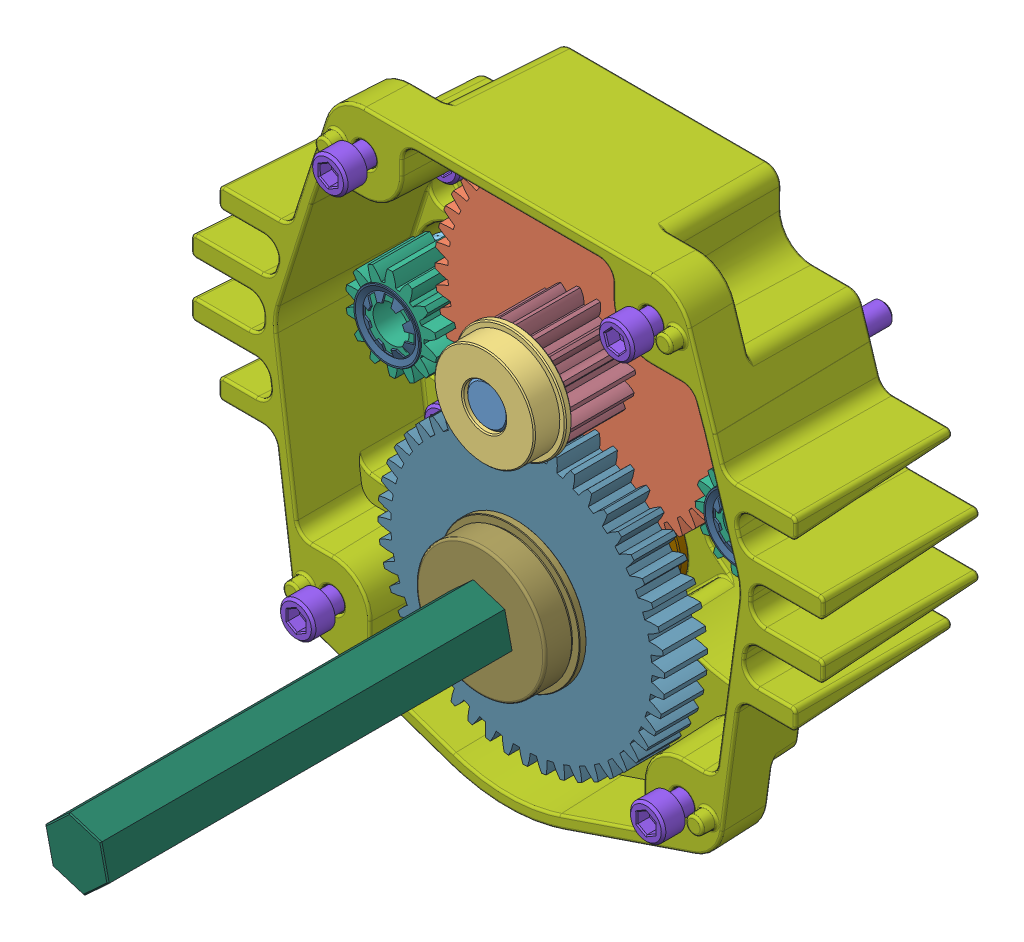
SolidWorks assembly ToughboxMini, configuration Default. Lengths in mm.
Overall size (140.05 127.01 142.29).
31 component instances, 15 part files, 74 mates.
Components (placement in the parent):
- TBMiniSmallHexShaft-1: TBMiniSmallHexShaft [Default] at (-129.7894 33.1737 -52.3959) x (-0.674239 -0.738513 0) z (-0.738513 0.674239 0) size (11 38.23 9.52)
- LargeClusterGear_Hex_50t0.375-1: LargeClusterGear_Hex_50t0.375 [Default] at (-91.0349 50.9043 -67.5597) x (-0.674239 -0.738513 0) z (0 0 -1) size (65.97 66.04 10.16)
- Bearing_FR6ZZ-1: Bearing_FR6ZZ [Default] at (-96.247 60.278 -52.5991) x (-0.893862 0.448342 0) z (0 0 1) size (24.69 24.69 7.16)
- NylockNut_10-32-1: NylockNut_10-32 [Default] at (-129.8464 -8.0737 -56.3837) x (0.501678 0.865055 0) z (0 0 -1) size (10.18 11.01 7.1)
- NylockNut_10-32-2: NylockNut_10-32 [Default] at (-59.2462 80.7349 -56.3837) x (0.999999 -0.001296 0) z (0 0 -1) size (10.18 11.01 7.1)
- NylockNut_10-32-3: NylockNut_10-32 [Default] at (-122.7461 80.8172 -56.3837) x (0.500567 0.865698 0) z (0 0 -1) size (10.18 11.01 7.1)
- NylockNut_10-32-4: NylockNut_10-32 [Default] at (-52.3764 -8.1741 -56.3837) x (-0.501678 -0.865055 0) z (0 0 -1) size (10.18 11.01 7.1)
- Washer_5-16-1: Washer_5-16 [Default] at (-52.3162 38.3079 -77.7705) x (-0.418041 0.908428 0) z (0 0 -1) size (17.53 17.53 1.47)
- Washer_5-16-2: Washer_5-16 [Default] at (-52.3162 38.3079 -76.2973) x (0.897267 -0.441488 0) z (0 0 -1) size (17.53 17.53 1.47)
- Washer_5-16-3: Washer_5-16 [Default] at (-129.7861 38.4083 -77.7705) x (-0.990116 0.140253 0) z (0 0 1) size (17.53 17.53 1.47)
- Washer_5-16-4: Washer_5-16 [Default] at (-129.7861 38.4083 -79.2437) x (-0.681761 0.731575 0) z (0 0 1) size (17.53 17.53 1.47)
- CIMGear_14t8mm-1: CIMGear_14t8mm [Default] at (-52.3162 38.3079 -63.5973) x (-0.082762 0.996569 0) z (0 0 -1) size (20.03 20.32 12.7)
- CIMGear_14t8mm-2: CIMGear_14t8mm [Default] at (-129.7861 38.4083 -63.5973) x (0.603285 0.797525 0) z (0 0 -1) size (20.03 20.32 12.7)
- TBMiniHousing-1: TBMiniHousing [Default] at (-91.0876 10.1882 -86.3557) x (0.999999 -0.001296 0) z (0 0 1) size (139.9 118.55 41.54)
- Screw_SHCS_10-32x0.625-1: Screw_SHCS_10-32x0.625 [Default] at (-52.2832 63.7078 -74.4685) x (-0.564778 -0.825243 0) z (-0.825243 0.564778 0) size (7.82 20.65 7.82)
- Screw_SHCS_10-32x0.625-2: Screw_SHCS_10-32x0.625 [Default] at (-122.7461 80.8172 -42.5915) x (0.507484 -0.861661 0) z (-0.861661 -0.507484 0) size (7.82 20.65 7.82)
- Screw_SHCS_10-32x0.625-3: Screw_SHCS_10-32x0.625 [Default] at (-52.3764 -8.1741 -42.5915) x (0.507484 -0.861661 0) z (-0.861661 -0.507484 0) size (7.82 20.65 7.82)
- Screw_SHCS_10-32x0.625-4: Screw_SHCS_10-32x0.625 [Default] at (-129.8464 -8.0737 -42.5915) x (0.507484 -0.861661 0) z (-0.861661 -0.507484 0) size (7.82 20.65 7.82)
- Screw_SHCS_10-32x0.625-5: Screw_SHCS_10-32x0.625 [Default] at (-59.2462 80.7349 -42.5915) x (0.740711 -0.671824 0) z (-0.671824 -0.740711 0) size (7.82 20.65 7.82)
- Screw_SHCS_10-32x0.625-6: Screw_SHCS_10-32x0.625 [Default] at (-52.3491 12.9079 -74.4685) x (-0.564778 -0.825243 0) z (-0.825243 0.564778 0) size (7.82 20.65 7.82)
- Screw_SHCS_10-32x0.625-7: Screw_SHCS_10-32x0.625 [Default] at (-129.7532 63.8083 -74.4685) x (-0.966277 -0.257503 0) z (-0.257503 0.966277 0) size (7.82 20.65 7.82)
- Screw_SHCS_10-32x0.625-8: Screw_SHCS_10-32x0.625 [Default] at (-129.819 13.0083 -74.4685) x (-0.99652 0.083357 0) z (0.083357 0.99652 0) size (7.82 20.65 7.82)
- Bearing_R6ZZ-3: Bearing_R6ZZ [Default] at (-91.0349 50.9043 -84.8317) x (0.958138 -0.286306 0) z (0 0 1) size (22.23 22.23 7.11)
- Bearing_R6ZZ-4: Bearing_R6ZZ [Default] at (-91.0876 10.1882 -84.8317) x (-0.661529 0.74992 0) z (0 0 1) size (22.23 22.23 7.11)
- RetainingClip-1: RetainingClip [Default] at (-129.7861 38.4083 -63.5973) x (0 0 1) z (-1 0 0) size (1.09 14.83 14.83)
- RetainingClip-2: RetainingClip [Default] at (-52.3162 38.3079 -63.5973) x (0 0 1) z (-1 0 0) size (1.09 14.83 14.83)
- ExternalKlipring-1: ExternalKlipring [Default] at (-91.0876 10.1882 -64.4355) x (0.996411 -0.084651 0) z (0 0 1) size (19.07 20.96 1.27)
- HexBearing_FR8ZZ-1: HexBearing_FR8ZZ [Default] at (-91.0876 10.1882 -44.6717) x (0.73373 0.679441 0) z (0 0 -1) size (31.12 31.12 7.93)
- SmallClusterGear_Hex_16t0.375-1: SmallClusterGear_Hex_16t0.375 [Default] at (-91.0349 50.9043 -67.5597) x (0 0 1) z (0.302452 -0.953165 0) size (15.19 22.57 22.57)
- LargeOutputGear_Hex_48t0.5-1: LargeOutputGear_Hex_48t0.5 [Default] at (-91.0876 10.1882 -63.1655) x (0 0 1) z (-0.955278 0.295708 0) size (10.21 63.42 63.42)
- TBMiniHexOutputShaft-2: TBMiniHexOutputShaft [Default] at (-51.6549 23.9851 -52.3197) x (0.73373 0.679441 0) z (0.679441 -0.73373 0) size (14.66 142.29 12.7)
Mates (geometry in assembly coordinates):
- Concentric2: concentric aligned: circle of NylockNut_10-32-3; circle of TBMiniHousing-1
- Coincident1: coincident anti-aligned: plane of NylockNut_10-32-3 through (-122.7461 80.8172 -56.3837) normal (0 0 1); plane of TBMiniHousing-1 through (-132.6301 80.83 -56.3837) normal (0 0 -1)
- Parallel1: parallel: plane of NylockNut_10-32-3 through (-125.1247 84.9432 -58.368) normal (-0.499433 0.866352 0); line of TBMiniHousing-1 through (-122.993 86.3757 -60.7105) axis (-0.866352 -0.499433 0)
- Concentric3: concentric anti-aligned: circle of NylockNut_10-32-2; circle of TBMiniHousing-1
- Coincident3: coincident anti-aligned: plane of NylockNut_10-32-2 through (-59.2462 80.7349 -56.3837) normal (0 0 1); plane of TBMiniHousing-1 through (-59.2388 86.4499 -56.3837) normal (0 0 -1)
- Parallel2: parallel: plane of NylockNut_10-32-2 through (-54.4837 80.7287 -58.368) normal (0.999999 -0.001296 0); line of TBMiniHousing-1 through (-54.0512 78.1748 -60.9557) axis (0.001296 0.999999 0)
- Concentric4: concentric anti-aligned: circle of NylockNut_10-32-4; circle of TBMiniHousing-1
- Coincident5: coincident anti-aligned: plane of NylockNut_10-32-4 through (-52.3764 -8.1741 -56.3837) normal (0 0 1); plane of TBMiniHousing-1 through (-62.2604 -8.1613 -56.3837) normal (0 0 -1)
- Parallel3: parallel: plane of NylockNut_10-32-4 through (-49.9872 -4.0543 -58.368) normal (0.501678 0.865055 0); line of TBMiniHousing-1 through (-47.5543 -4.9678 -60.9557) axis (-0.865055 0.501678 0)
- Concentric5: concentric aligned: circle of NylockNut_10-32-1; circle of TBMiniHousing-1
- Coincident9: coincident anti-aligned: plane of NylockNut_10-32-1 through (-129.8464 -8.0737 -56.3837) normal (0 0 1); plane of TBMiniHousing-1 through (-139.7304 -8.0609 -56.3837) normal (0 0 -1)
- Parallel4: parallel: plane of NylockNut_10-32-1 through (-132.2356 -12.1935 -58.368) normal (-0.501678 -0.865055 0); line of TBMiniHousing-1 through (-130.235 -13.8511 -60.9557) axis (-0.865055 0.501678 0)
- Concentric6: concentric aligned: cylinder of TBMiniHousing-1 through (-129.7532 63.8083 -50.5417) axis (0 0 1) radius 2.5527; circle of Screw_SHCS_10-32x0.625-7
- Coincident11: coincident anti-aligned: plane of TBMiniHousing-1 through (-59.2462 80.7349 -79.2437) normal (0 0 1); plane of Screw_SHCS_10-32x0.625-7 through (-129.7532 63.8083 -79.2437) normal (0 0 -1)
- Concentric7: concentric anti-aligned: cylinder of TBMiniHousing-1 through (-52.2832 63.7078 -50.5417) axis (0 0 1) radius 2.5527; circle of Screw_SHCS_10-32x0.625-1
- Coincident12: coincident anti-aligned: plane of TBMiniHousing-1 through (-59.2462 80.7349 -79.2437) normal (0 0 1); plane of Screw_SHCS_10-32x0.625-1 through (-52.2832 63.7078 -79.2437) normal (0 0 -1)
- Concentric8: concentric aligned: cylinder of TBMiniHousing-1 through (-52.3491 12.9079 -50.5417) axis (0 0 1) radius 2.5527; cylinder of Screw_SHCS_10-32x0.625-6 through (-52.3491 12.9079 -95.1187) axis (0 0 1) radius 2.3876
- Coincident13: coincident anti-aligned: plane of TBMiniHousing-1 through (-59.2462 80.7349 -79.2437) normal (0 0 1); plane of Screw_SHCS_10-32x0.625-6 through (-52.3491 12.9079 -79.2437) normal (0 0 -1)
- Concentric9: concentric aligned: cylinder of TBMiniHousing-1 through (-129.819 13.0083 -50.5417) axis (0 0 1) radius 2.5527; cylinder of Screw_SHCS_10-32x0.625-8 through (-129.819 13.0083 -95.1187) axis (0 0 1) radius 2.3876
- Coincident14: coincident anti-aligned: plane of TBMiniHousing-1 through (-59.2462 80.7349 -79.2437) normal (0 0 1); plane of Screw_SHCS_10-32x0.625-8 through (-129.819 13.0083 -79.2437) normal (0 0 -1)
- Concentric12: concentric aligned: cylinder of Washer_5-16-3 through (-129.7861 38.4083 -76.2973) axis (0 0 -1) radius 8.763; cylinder of Washer_5-16-4 through (-129.7861 38.4083 -77.7705) axis (0 0 -1) radius 8.763
- Concentric13: concentric anti-aligned: circle of Washer_5-16-4; cylinder of TBMiniHousing-1 through (-129.7861 38.4083 -50.5417) axis (0 0 1) radius 10.414
- Coincident17: coincident anti-aligned: plane of Washer_5-16-4 through (-129.7861 38.4083 -79.2437) normal (0 0 -1); plane of TBMiniHousing-1 through (-59.2462 80.7349 -79.2437) normal (0 0 1)
- Coincident18: coincident anti-aligned: plane of Washer_5-16-3 through (-129.7861 38.4083 -77.7705) normal (0 0 -1); plane of Washer_5-16-4 through (-129.7861 38.4083 -77.7705) normal (0 0 1)
- Concentric14: concentric anti-aligned: circle of Washer_5-16-3; circle of CIMGear_14t8mm-2
- Coincident19: coincident anti-aligned: plane of Washer_5-16-3 through (-129.7861 38.4083 -76.2973) normal (0 0 1); plane of CIMGear_14t8mm-2 through (-129.7861 38.4083 -76.2973) normal (0 0 -1)
- Coincident21: coincident aligned: circle of Washer_5-16-1; circle of Washer_5-16-2
- Concentric16: concentric aligned: cylinder of Washer_5-16-1 through (-52.3162 38.3079 -79.2437) axis (0 0 1) radius 4.3942; cylinder of TBMiniHousing-1 through (-52.3162 38.3079 -50.5417) axis (0 0 1) radius 10.414
- Coincident22: coincident anti-aligned: plane of Washer_5-16-1 through (-52.3162 38.3079 -79.2437) normal (0 0 -1); plane of TBMiniHousing-1 through (-59.2462 80.7349 -79.2437) normal (0 0 1)
- Coincident23: coincident aligned: plane of Washer_5-16-2 through (-52.3162 38.3079 -76.2973) normal (0 0 1); circle of CIMGear_14t8mm-1
- Concentric17: concentric aligned: circle of Washer_5-16-2; cylinder of CIMGear_14t8mm-1 through (-52.3162 38.3079 -76.2973) axis (0 0 1) radius 4
- Parallel5: parallel anti-aligned: plane of TBMiniSmallHexShaft-1 through (-96.4059 52.0847 -77.9229) normal (-0.953165 -0.302452 0); plane of LargeClusterGear_Hex_50t0.375-1 through (-96.4059 52.0847 -67.5597) normal (0.953165 0.302452 0)
- Concentric20: concentric anti-aligned: circle of TBMiniSmallHexShaft-1; circle of LargeClusterGear_Hex_50t0.375-1
- Concentric27: concentric anti-aligned: cylinder of TBMiniSmallHexShaft-1 through (-91.0349 50.9043 -46.0459) axis (0 0 -1) radius 4.7498; cylinder of Bearing_FR6ZZ-1 through (-91.0349 50.9043 -51.0751) axis (0 0 1) radius 4.7625
- Coincident37: coincident aligned: plane of Screw_SHCS_10-32x0.625-4 through (-129.8464 -8.0737 -47.3667) normal (0 0 -1); plane of Screw_SHCS_10-32x0.625-5 through (-59.2462 80.7349 -47.3667) normal (0 0 -1)
- Coincident39: coincident aligned: plane of Screw_SHCS_10-32x0.625-2 through (-122.7461 80.8172 -47.3667) normal (0 0 -1); plane of Screw_SHCS_10-32x0.625-5 through (-59.2462 80.7349 -47.3667) normal (0 0 -1)
- Coincident40: coincident aligned: plane of Screw_SHCS_10-32x0.625-2 through (-122.7461 80.8172 -47.3667) normal (0 0 -1); plane of Screw_SHCS_10-32x0.625-3 through (-52.3764 -8.1741 -47.3667) normal (0 0 -1)
- Concentric34: concentric anti-aligned: cylinder of TBMiniSmallHexShaft-1 through (-91.0349 50.9043 -84.2729) axis (0 0 1) radius 4.7498; cylinder of Bearing_R6ZZ-3 through (-91.0349 50.9043 -77.7197) axis (0 0 -1) radius 11.1125
- Coincident49: coincident anti-aligned: plane of CIMGear_14t8mm-2 through (-129.7861 38.4083 -63.5973) normal (0 0 1); circle of RetainingClip-1
- Concentric36: concentric aligned: circle of CIMGear_14t8mm-2; circle of RetainingClip-1
- Coincident50: coincident anti-aligned: plane of CIMGear_14t8mm-1 through (-52.3162 38.3079 -63.5973) normal (0 0 1); circle of RetainingClip-2
- Concentric37: concentric aligned: circle of CIMGear_14t8mm-1; circle of RetainingClip-2
- Concentric48: concentric anti-aligned: cylinder of TBMiniHousing-1 through (-91.0876 10.1882 -50.5417) axis (0 0 1) radius 5.08; cylinder of Bearing_R6ZZ-4 through (-91.0876 10.1882 -77.7197) axis (0 0 -1) radius 11.1125
- Coincident60: coincident anti-aligned: plane of TBMiniHousing-1 through (-91.0876 10.1882 -84.8317) normal (0 0 1); plane of Bearing_R6ZZ-4 through (-91.0876 10.1882 -84.8317) normal (0 0 -1)
- Coincident62: coincident aligned: plane of Bearing_FR6ZZ-1 through (-91.0349 50.9043 -51.0751) normal (0 0 1); plane of HexBearing_FR8ZZ-1 through (-80.8374 19.68 -51.0751) normal (0 0 1)
- Coincident63: coincident anti-aligned: plane of TBMiniHousing-1 through (-91.0349 50.9043 -84.8317) normal (0 0 1); plane of Bearing_R6ZZ-3 through (-91.0349 50.9043 -84.8317) normal (0 0 -1)
- Coincident64: coincident anti-aligned: plane of TBMiniSmallHexShaft-1 through (-92.6981 56.146 -77.7197) normal (0 0 -1); plane of Bearing_R6ZZ-3 through (-91.0349 50.9043 -77.7197) normal (0 0 1)
- Coincident66: coincident anti-aligned: plane of LargeClusterGear_Hex_50t0.375-1 through (-91.0349 50.9043 -77.7197) normal (0 0 -1); plane of Bearing_R6ZZ-3 through (-91.0349 50.9043 -77.7197) normal (0 0 1)
- Coincident69: coincident anti-aligned: plane of TBMiniSmallHexShaft-1 through (-87.327 54.9656 -52.5991) normal (0 0 1); plane of Bearing_FR6ZZ-1 through (-91.0349 50.9043 -52.5991) normal (0 0 -1)
- Concentric52: concentric aligned: cylinder of TBMiniHousing-1 through (-91.0349 50.9043 -84.8317) axis (0 0 -1) radius 11.1061; cylinder of Bearing_R6ZZ-3 through (-91.0349 50.9043 -77.7197) axis (0 0 -1) radius 11.1125
- Distance1: distance = 3.175 mm anti-aligned: plane of TBMiniHousing-1 through (-91.0876 10.1882 -50.5417) normal (0 0 1); plane of Screw_SHCS_10-32x0.625-5 through (-59.2462 80.7349 -47.3667) normal (0 0 -1)
- Concentric53: concentric aligned: cone of TBMiniHousing-1 through (-59.2462 80.7349 -55.8934) axis (0 0 1); cylinder of Screw_SHCS_10-32x0.625-5 through (-59.2462 80.7349 -47.3667) axis (0 0 1) radius 3.9116
- Coincident71: coincident aligned: plane of Screw_SHCS_10-32x0.625-2 through (-122.7461 80.8172 -42.5915) normal (0 0 1); plane of Screw_SHCS_10-32x0.625-5 through (-59.2462 80.7349 -42.5915) normal (0 0 1)
- Concentric54: concentric aligned: cone of TBMiniHousing-1 through (-122.7461 80.8172 -55.8934) axis (0 0 1); cylinder of Screw_SHCS_10-32x0.625-2 through (-122.7461 80.8172 -47.3667) axis (0 0 1) radius 3.9116
- Coincident72: coincident aligned: plane of Screw_SHCS_10-32x0.625-3 through (-52.3764 -8.1741 -42.5915) normal (0 0 1); plane of Screw_SHCS_10-32x0.625-5 through (-59.2462 80.7349 -42.5915) normal (0 0 1)
- Concentric55: concentric aligned: cone of TBMiniHousing-1 through (-52.3764 -8.1741 -55.8934) axis (0 0 1); cylinder of Screw_SHCS_10-32x0.625-3 through (-52.3764 -8.1741 -47.3667) axis (0 0 1) radius 3.9116
- Coincident73: coincident aligned: plane of Screw_SHCS_10-32x0.625-2 through (-122.7461 80.8172 -42.5915) normal (0 0 1); plane of Screw_SHCS_10-32x0.625-4 through (-129.8464 -8.0737 -42.5915) normal (0 0 1)
- Concentric56: concentric aligned: cone of TBMiniHousing-1 through (-129.8464 -8.0737 -55.8934) axis (0 0 1); cylinder of Screw_SHCS_10-32x0.625-4 through (-129.8464 -8.0737 -63.2417) axis (0 0 1) radius 2.3876
- Parallel6: parallel aligned: plane of TBMiniSmallHexShaft-1 through (-96.4059 52.0847 -77.9229) normal (-0.953165 -0.302452 0); plane of SmallClusterGear_Hex_16t0.375-1 through (-85.6638 49.7239 -67.5597) normal (-0.953165 -0.302452 0)
- Coincident75: coincident anti-aligned: plane of LargeClusterGear_Hex_50t0.375-1 through (-91.0349 50.9043 -67.5597) normal (0 0 1); plane of SmallClusterGear_Hex_16t0.375-1 through (-91.0349 50.9043 -67.5597) normal (0 0 -1)
- Concentric58: concentric anti-aligned: cylinder of HexBearing_FR8ZZ-1 through (-91.0876 10.1882 -52.5991) axis (0 0 1) radius 14.2875; cylinder of LargeOutputGear_Hex_48t0.5-1 through (-91.0876 10.1882 -52.9547) axis (0 0 -1) radius 8.89
- Coincident77: coincident anti-aligned: plane of ExternalKlipring-1 through (-91.0876 10.1882 -63.1655) normal (0 0 1); plane of LargeOutputGear_Hex_48t0.5-1 through (-91.0876 10.1882 -63.1655) normal (0 0 -1)
- Concentric59: concentric aligned: cylinder of Bearing_FR6ZZ-1 through (-91.0349 50.9043 -45.4363) axis (0 0 1) radius 11.1125; circle of SmallClusterGear_Hex_16t0.375-1
- Coincident80: coincident anti-aligned: plane of ExternalKlipring-1 through (-91.0876 10.1882 -63.1655) normal (0 0 1); plane of LargeOutputGear_Hex_48t0.5-1 through (-91.0876 10.1882 -63.1655) normal (0 0 -1)
- Concentric62: concentric anti-aligned: cylinder of Bearing_R6ZZ-4 through (-91.0876 10.1882 -77.7197) axis (0 0 -1) radius 11.1125; cylinder of HexBearing_FR8ZZ-1 through (-91.0876 10.1882 -52.5991) axis (0 0 1) radius 14.2875
- Concentric63: concentric anti-aligned: cylinder of Bearing_R6ZZ-4 through (-91.0876 10.1882 -77.7197) axis (0 0 -1) radius 4.7625; cylinder of TBMiniHexOutputShaft-2 through (-91.0876 10.1882 -84.8317) axis (0 0 1) radius 4.7498
- Coincident82: coincident anti-aligned: plane of Bearing_R6ZZ-4 through (-91.0876 10.1882 -77.7197) normal (0 0 1); plane of TBMiniHexOutputShaft-2 through (-82.4587 0.8698 -77.7197) normal (0 0 -1)
- Coincident83: coincident anti-aligned: plane of HexBearing_FR8ZZ-1 through (-92.7121 17.3383 -52.5991) normal (0.679441 -0.73373 0); plane of TBMiniHexOutputShaft-2 through (-92.7121 17.3383 -77.7197) normal (-0.679441 0.73373 0)
- Coincident84: coincident anti-aligned: plane of LargeOutputGear_Hex_48t0.5-1 through (-95.4021 14.8473 -63.1655) normal (0.679441 -0.73373 0); plane of TBMiniHexOutputShaft-2 through (-92.7121 17.3383 -77.7197) normal (-0.679441 0.73373 0)
- Concentric64: concentric anti-aligned: cylinder of ExternalKlipring-1 through (-91.0876 10.1882 -63.1655) axis (0 0 -1) radius 5.1562; cylinder of TBMiniHexOutputShaft-2 through (-91.0876 10.1882 -77.7197) axis (0 0 1) radius 5.588
- Coincident85: coincident anti-aligned: plane of ExternalKlipring-1 through (-91.0876 10.1882 -64.4355) normal (0 0 -1); plane of TBMiniHexOutputShaft-2 through (-78.9672 21.4118 -64.4355) normal (0 0 1)
- GearMate1: gear = 1219.2 : 406.4 mm: circle of SmallClusterGear_Hex_16t0.375-1; cylinder of LargeOutputGear_Hex_48t0.5-1 through (-91.0876 10.1882 -52.9547) axis (0 0 -1) radius 8.89
- GearMate2: gear = 355.6 : 1270 mm: circle of LargeClusterGear_Hex_50t0.375-1; cylinder of CIMGear_14t8mm-2 through (-129.7861 38.4083 -76.2973) axis (0 0 1) radius 4
- GearMate3: gear = 355.6 : 1270 mm: circle of LargeClusterGear_Hex_50t0.375-1; cylinder of CIMGear_14t8mm-1 through (-52.3162 38.3079 -76.2973) axis (0 0 1) radius 4
